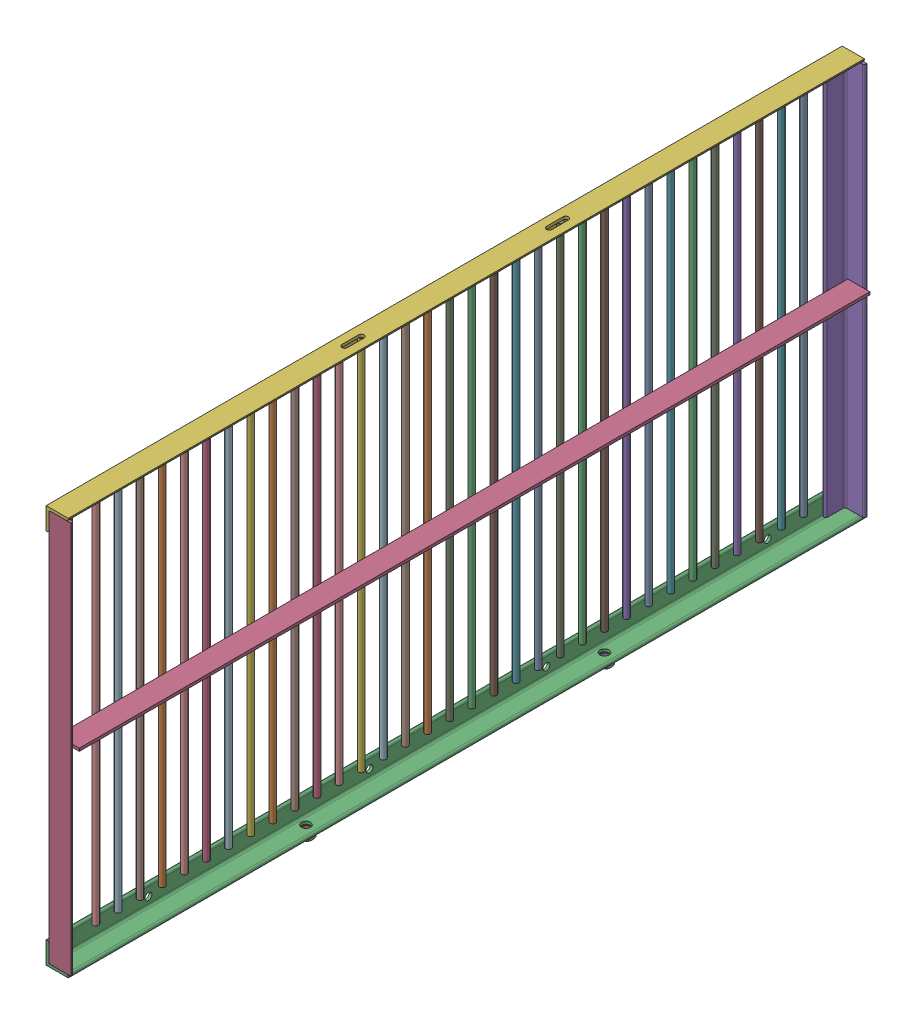
SolidWorks assembly 01-070-00-0, configuration Default. Lengths in mm.
Overall size (69.85 931.29 1828.8).
40 component instances, 6 part files, 0 mates.
Components (placement in the parent):
- hex nut_ai(HNUT 0.7500-10-D-C)-1: hex nut_ai(HNUT 0.7500-10-D-C) [Default] at (25.4 -16.891 -342.9) x (1 0 0) z (0 -1 0) size (28.57 33 16.89)
- hex nut_ai(HNUT 0.7500-10-D-C)-2: hex nut_ai(HNUT 0.7500-10-D-C) [Default] at (25.4 -16.891 342.9) x (1 0 0) z (0 -1 0) size (28.57 33 16.89)
- 01-068-00-0-1: 01-068-00-0 [Default] at origin size (50.8 50.8 1828.8)
- 01-069-00-0-1: 01-069-00-0 [Default] at (6.35 457.2 914.4) x (1 0 0) z (0 1 0) size (50.8 50.8 901.7)
- 01-069-00-0-2: 01-069-00-0 [Default] at (6.35 457.2 -914.4) x (1 0 0) z (0 -1 0) size (50.8 50.8 901.7)
- 01-086-00-0-1: 01-086-00-0 [Default] at (0 914.4 0) x (1 0 0) z (0 0 -1) size (50.8 50.8 1828.8)
- 01-071-00-0-1: 01-071-00-0 [Default] at (12.7 469.9 -152.4) size (12.7 863.6 12.7)
- 01-071-00-0-2: 01-071-00-0 [Default] at (12.7 469.9 711.2) size (12.7 863.6 12.7)
- 01-071-00-0-3: 01-071-00-0 [Default] at (12.7 469.9 -254) size (12.7 863.6 12.7)
- 01-071-00-0-4: 01-071-00-0 [Default] at (12.7 469.9 609.6) size (12.7 863.6 12.7)
- 01-071-00-0-5: 01-071-00-0 [Default] at (12.7 469.9 -355.6) size (12.7 863.6 12.7)
- 01-071-00-0-6: 01-071-00-0 [Default] at (12.7 469.9 508) size (12.7 863.6 12.7)
- 01-071-00-0-7: 01-071-00-0 [Default] at (12.7 469.9 -457.2) size (12.7 863.6 12.7)
- 01-071-00-0-8: 01-071-00-0 [Default] at (12.7 469.9 406.4) size (12.7 863.6 12.7)
- 01-071-00-0-9: 01-071-00-0 [Default] at (12.7 469.9 -558.8) size (12.7 863.6 12.7)
- 01-071-00-0-10: 01-071-00-0 [Default] at (12.7 469.9 304.8) size (12.7 863.6 12.7)
- 01-071-00-0-11: 01-071-00-0 [Default] at (12.7 469.9 -660.4) size (12.7 863.6 12.7)
- 01-071-00-0-12: 01-071-00-0 [Default] at (12.7 469.9 203.2) size (12.7 863.6 12.7)
- 01-071-00-0-13: 01-071-00-0 [Default] at (12.7 469.9 -762) size (12.7 863.6 12.7)
- 01-071-00-0-14: 01-071-00-0 [Default] at (12.7 469.9 101.6) size (12.7 863.6 12.7)
- 01-071-00-0-15: 01-071-00-0 [Default] at (12.7 469.9 0) size (12.7 863.6 12.7)
- 01-071-00-0-16: 01-071-00-0 [Default] at (12.7 469.9 812.8) size (12.7 863.6 12.7)
- 01-071-00-0-17: 01-071-00-0 [Default] at (12.7 469.9 -101.6) size (12.7 863.6 12.7)
- 01-071-00-0-18: 01-071-00-0 [Default] at (12.7 469.9 762) size (12.7 863.6 12.7)
- 01-071-00-0-19: 01-071-00-0 [Default] at (12.7 469.9 -203.2) size (12.7 863.6 12.7)
- 01-071-00-0-20: 01-071-00-0 [Default] at (12.7 469.9 660.4) size (12.7 863.6 12.7)
- 01-071-00-0-21: 01-071-00-0 [Default] at (12.7 469.9 -304.8) size (12.7 863.6 12.7)
- 01-071-00-0-22: 01-071-00-0 [Default] at (12.7 469.9 558.8) size (12.7 863.6 12.7)
- 01-071-00-0-23: 01-071-00-0 [Default] at (12.7 469.9 -406.4) size (12.7 863.6 12.7)
- 01-071-00-0-24: 01-071-00-0 [Default] at (12.7 469.9 457.2) size (12.7 863.6 12.7)
- 01-071-00-0-25: 01-071-00-0 [Default] at (12.7 469.9 -508) size (12.7 863.6 12.7)
- 01-071-00-0-26: 01-071-00-0 [Default] at (12.7 469.9 355.6) size (12.7 863.6 12.7)
- 01-071-00-0-27: 01-071-00-0 [Default] at (12.7 469.9 -609.6) size (12.7 863.6 12.7)
- 01-071-00-0-28: 01-071-00-0 [Default] at (12.7 469.9 254) size (12.7 863.6 12.7)
- 01-071-00-0-29: 01-071-00-0 [Default] at (12.7 469.9 -711.2) size (12.7 863.6 12.7)
- 01-071-00-0-30: 01-071-00-0 [Default] at (12.7 469.9 152.4) size (12.7 863.6 12.7)
- 01-071-00-0-31: 01-071-00-0 [Default] at (12.7 469.9 -812.8) size (12.7 863.6 12.7)
- 01-071-00-0-32: 01-071-00-0 [Default] at (12.7 469.9 50.8) size (12.7 863.6 12.7)
- 01-071-00-0-33: 01-071-00-0 [Default] at (12.7 469.9 -50.8) size (12.7 863.6 12.7)
- 01-118-00-0-1: 01-118-00-0 [Default] at (19.05 457.2 -908.05) x (0 0 1) z (-1 0 0) size (1816.1 6.35 50.8)
